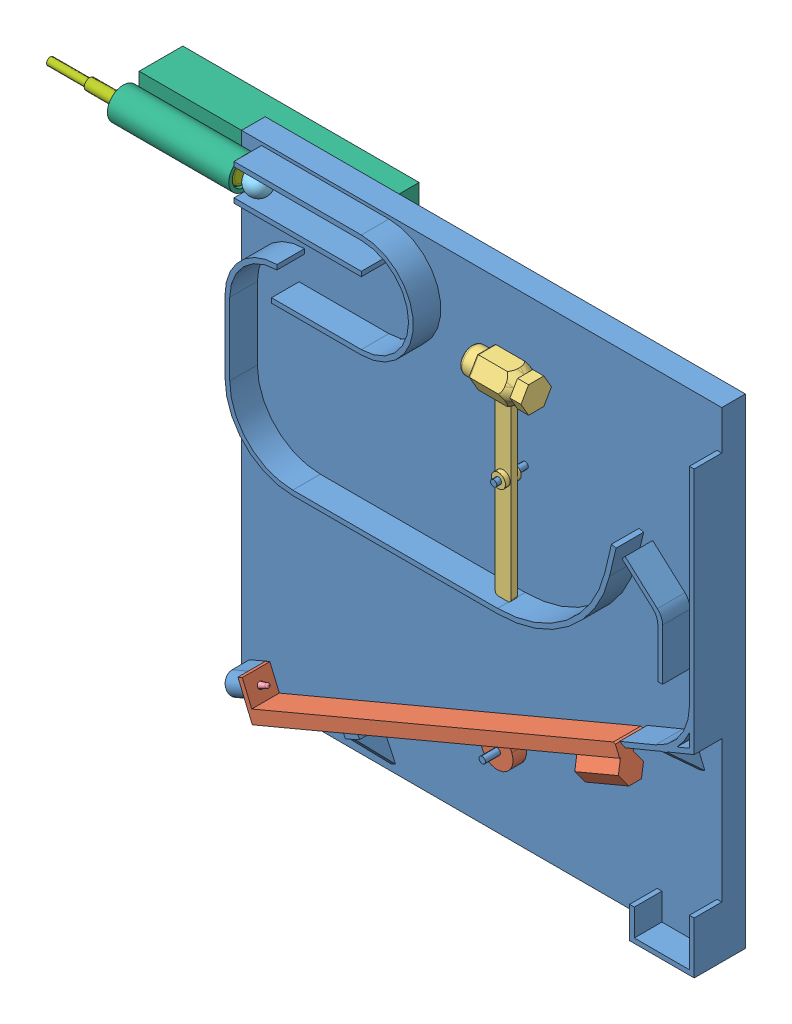
SolidWorks assembly Dimentioned Assembly, configuration Default. Lengths in mm.
Overall size (416.02 319.55 83.18).
7 component instances, 7 part files, 11 mates.
Components (placement in the parent):
- Dimentioned Design-1: Dimentioned Design [Default] at (-181.4879 -145.3138 30.5351) size (304.8 304.8 80)
- Dimentioned Ballance-1: Dimentioned Ballance [Default] at (-152.4142 -143.236 32.5351) x (0.921633 0.388063 0) z (0 0 1) size (253 40.5 21.03)
- Dimentioned Hammer-1: Dimentioned Hammer [Default] at (-6.4767 -1.025 42.5351) size (41 129.88 22.35)
- Dimentioned Pin-1: Dimentioned Pin [Default] at (-162.4393 -130.0797 41.5351) x (0.154378 -0.361311 -0.919577) z (0.919577 0.39291 0) size (4 4 27.5)
- Dimentioned Ball-1: Dimentioned Ball [Default] at (-161.3058 138.5091 38.5084) x (0.999979 -0.000666 0.006475) z (-0.006475 -0.203558 0.979041) size (15 15 15)
- Dimentioned Launcher-1: Dimentioned Launcher [Default] at (-246.4879 146.9862 30.5351) x (0 1 0) z (1 0 0) size (25 47.88 150)
- Dimentioned Plunger-2: Dimentioned Plunger [Default] at (-172.7058 146.9862 40.6955) x (0 -0.99868 0.051372) z (1 0 0) size (15 15 122.5)
Mates (geometry in assembly coordinates):
- Concentric1: concentric aligned: circle of Dimentioned Design-1; circle of Dimentioned Ballance-1
- Distance1: distance = 2 mm anti-aligned: plane of Dimentioned Design-1 through (-181.4879 -145.3138 30.5351) normal (0 0 1); plane of Dimentioned Ballance-1 through (-152.4142 -143.236 32.5351) normal (0 0 -1)
- Concentric2: concentric aligned: circle of Dimentioned Design-1; circle of Dimentioned Hammer-1
- Distance2: distance = 10 mm anti-aligned: plane of Dimentioned Hammer-1 through (-6.4767 -1.025 40.5351) normal (0 0 -1); plane of Dimentioned Design-1 through (-181.4879 -145.3138 30.5351) normal (0 0 1)
- Concentric3: concentric anti-aligned: cylinder of Dimentioned Design-1 through (-132.553 -117.3101 41.5351) axis (-0.919577 -0.39291 0) radius 2; cylinder of Dimentioned Pin-1 through (-178.5319 -136.9556 41.5351) axis (0.919577 0.39291 0) radius 2
- Distance3: distance = 5 mm aligned: plane of Dimentioned Pin-1 through (-178.5319 -136.9556 41.5351) normal (-0.919577 -0.39291 0); plane of Dimentioned Design-1 through (-171.3704 -140.9909 48.0351) normal (-0.919577 -0.39291 0)
- Distance4: distance = 2 mm anti-aligned: sphere of Dimentioned Ball-1; plane of Dimentioned Design-1 through (-181.4879 -145.3138 30.5351) normal (0 0 1)
- Coincident6: coincident anti-aligned: plane of Dimentioned Design-1 through (-181.4879 -145.3138 15.5351) normal (0 0 -1); plane of Dimentioned Launcher-1 through (-96.4879 146.9862 15.5351) normal (0 0 1)
- Coincident8: coincident anti-aligned: plane of Dimentioned Design-1 through (-181.4879 -145.3138 15.5351) normal (-1 0 0); plane of Dimentioned Launcher-1 through (-181.4879 146.9862 30.5351) normal (1 0 0)
- Coincident9: coincident aligned: plane of Dimentioned Design-1 through (-181.4879 159.4862 15.5351) normal (0 1 0); plane of Dimentioned Launcher-1 through (-181.4879 159.4862 30.5351) normal (0 1 0)
- Concentric4: concentric anti-aligned: cylinder of Dimentioned Launcher-1 through (-243.9879 146.9862 40.6955) axis (-1 0 0) radius 2.5; cylinder of Dimentioned Plunger-2 through (-292.7058 146.9862 40.6955) axis (1 0 0) radius 2.375
